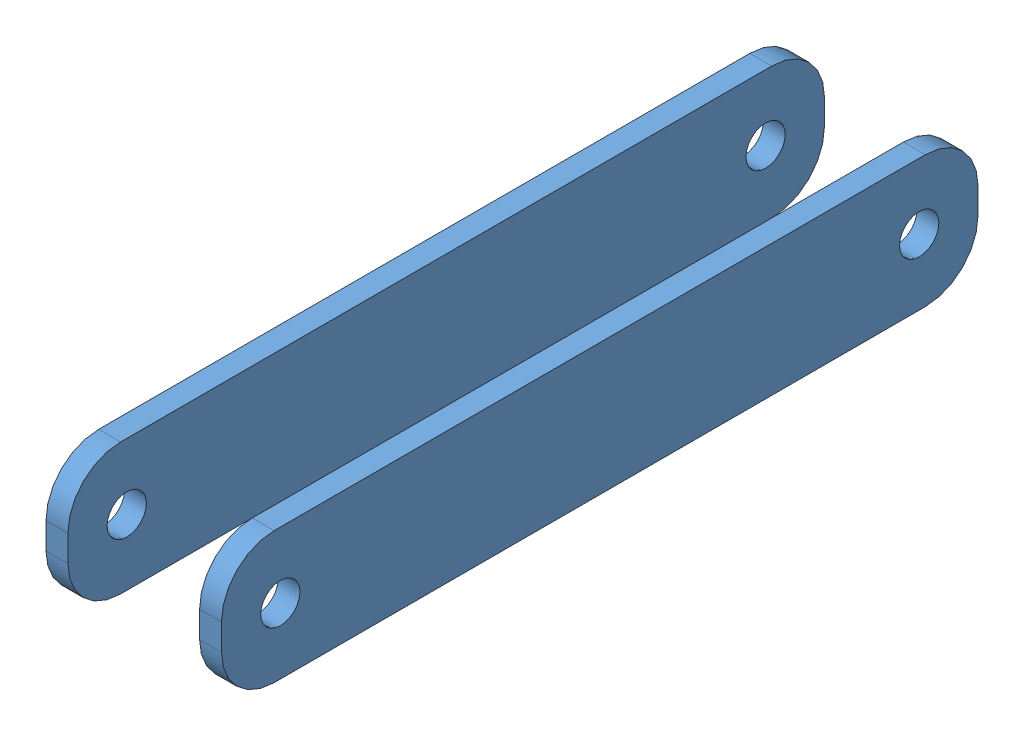
SolidWorks assembly l_gripper_fwd_link, configuration Default. Lengths in mm.
Overall size (12.7 9.53 54.74).
2 component instances, 1 part files, 4 mates.
Components (placement in the parent):
- gripper_link_forward-1: gripper_link_forward [Default] at (-1.5875 4.7625 -4.2545) x (0 0 1) z (0 1 0) size (54.74 1.59 9.53)
- gripper_link_forward-2: gripper_link_forward [Default] at (-12.7 4.7625 -4.2545) x (0 0 1) z (0 1 0) size (54.74 1.59 9.53)
Mates (geometry in assembly coordinates):
- Coincident2: coordinate: point of gripper_link_forward-1; point of assembly
- Concentric2: concentric: cylinder of gripper_link_forward-1 through (-1.5875 0 46.228) axis (1 0 0) radius 1.4224; cylinder of gripper_link_forward-2 through (-12.7 0 46.228) axis (1 0 0) radius 1.4224
- Distance2: distance = 12.7 mm: plane of gripper_link_forward-1 through (0 -4.7625 -4.2545) normal (1 0 0); plane of gripper_link_forward-2 through (-12.7 -4.7625 -4.2545) normal (-1 0 0)
- Concentric3: concentric aligned: cylinder of gripper_link_forward-1 through (-1.5875 0 0) axis (1 0 0) radius 1.4224; cylinder of gripper_link_forward-2 through (-12.7 0 0) axis (1 0 0) radius 1.4224
